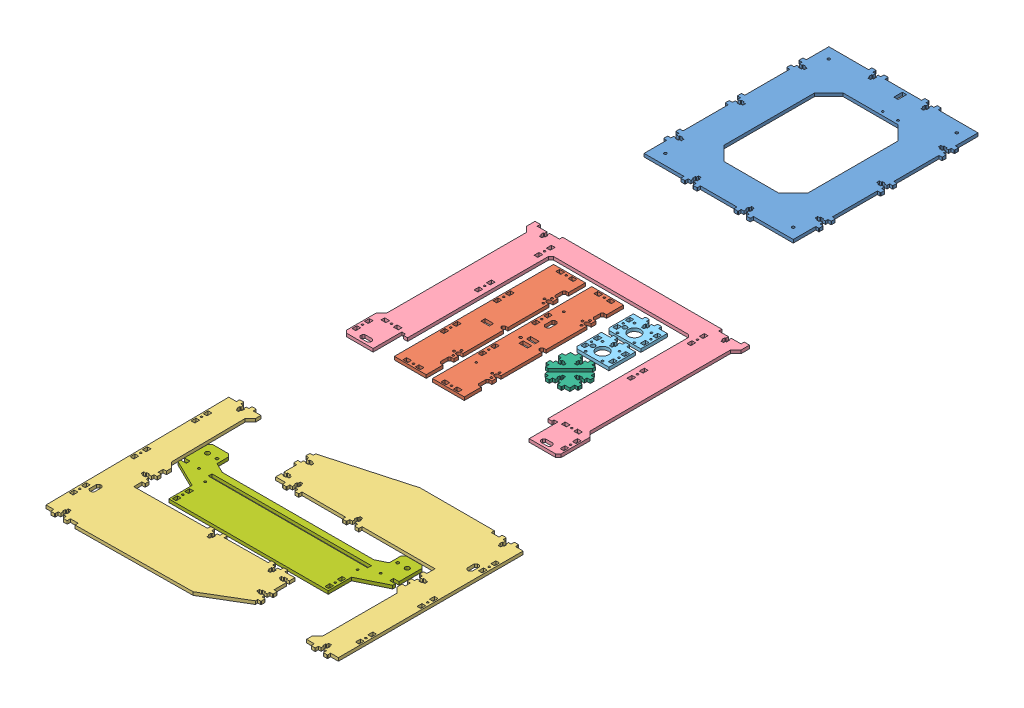
SolidWorks assembly frame_cut, configuration Défaut. Lengths in mm.
Overall size (619.45 6 1513.45).
11 component instances, 7 part files, 18 mates.
Components (placement in the parent):
- frame_bottom-1: frame_bottom [Défaut] at (-159.4463 3 -569.6458) size (293 6 360)
- frame_face-1: frame_face [front] at (-105.9772 3 20.9916) x (0 0 1) z (0 1 0) size (300 60 6)
- frame_face-2: frame_face [rear] at (-178.0549 3 20.72) x (0 0 1) z (0 1 0) size (300 60 6)
- frame_side-1: frame_side [left] at (234.7931 3 540.945) x (0 -1 0) z (0 0 -1) size (6 360 360)
- frame_side-2: frame_side [right] at (-291.5281 3 567.2933) x (0 -1 0) z (0.01087 0 0.999941) size (6 360 360)
- frame_middle-1: frame_middle [Défaut] at (-89.8091 3 -142.0894) x (1 0 0) z (0 1 0) size (404 360 6)
- frame_z_motor-1: frame_z_motor [Défaut] at (-16.2154 3 -98.6938) x (1 0 0) z (0 0 -1) size (64 6 56)
- frame_z_motor_holder-1: frame_z_motor_holder [Défaut] at (-34.2399 3 52.0112) x (0 1 0) z (0 0 1) size (6 53 53)
- frame_top-1: frame_top [Défaut] at (-34.0501 0 571.4756) x (-1 0 0.000948) z (-0.000948 0 -1) size (404 6 130)
- frame_z_motor-4: frame_z_motor [Défaut] at (-16.2267 3 -38.6772) x (1 0 0) z (0 0 -1) size (64 6 56)
- frame_z_motor_holder-4: frame_z_motor_holder [Défaut] at (2.4152 3 3.4437) x (0 1 0) z (0 0 -1) size (6 53 53)
Mates (geometry in assembly coordinates):
- Coïncidente1: coincident anti-aligned: plane of assembly through (0 0 0) normal (0 1 0); plane of frame_middle-1 through (-89.8091 0 -142.0894) normal (0 -1 0)
- Coïncidente2: coincident anti-aligned: plane of assembly through (0 0 0) normal (0 1 0); plane of frame_top-1 through (-34.0501 0 571.4756) normal (0 -1 0)
- Coïncidente3: coincident anti-aligned: plane of assembly through (0 0 0) normal (0 1 0); plane of frame_face-2 through (-148.0549 0 -64.28) normal (0 -1 0)
- Coïncidente4: coincident anti-aligned: plane of assembly through (0 0 0) normal (0 1 0); plane of frame_face-1 through (-75.9772 0 -64.0084) normal (0 -1 0)
- Coïncidente5: coincident anti-aligned: plane of assembly through (0 0 0) normal (0 1 0); plane of frame_side-1 through (234.7931 0 540.945) normal (0 -1 0)
- Coïncidente6: coincident anti-aligned: plane of assembly through (0 0 0) normal (0 1 0); plane of frame_side-2 through (-291.5281 0 567.2933) normal (0 -1 0)
- Coïncidente7: coincident anti-aligned: plane of assembly through (0 0 0) normal (0 1 0); plane of frame_z_motor-1 through (-16.2154 0 -98.6938) normal (0 -1 0)
- Coïncidente8: coincident anti-aligned: plane of assembly through (0 0 0) normal (0 1 0); plane of frame_z_motor_holder-1 through (-34.2399 0 52.0112) normal (0 -1 0)
- Coïncidente9: coincident anti-aligned: plane of assembly through (0 0 0) normal (0 1 0); plane of frame_z_motor-4 through (-16.2267 0 -38.6772) normal (0 -1 0)
- Coïncidente10: coincident anti-aligned: plane of assembly through (0 0 0) normal (0 1 0); plane of frame_z_motor_holder-4 through (2.4152 0 3.4437) normal (0 -1 0)
- Coïncidente11: coincident anti-aligned: plane of frame_bottom-1 through (-159.4463 0 -569.6458) normal (0 -1 0); plane of assembly through (0 0 0) normal (0 1 0)
- Parallèle7: parallel aligned: line of frame_middle-1 through (-281.8091 6 -156.0894) axis (0 0 1); line of frame_face-2 through (-204.0549 6 -129.28) axis (0 0 1)
- Parallèle8: parallel aligned: line of frame_middle-1 through (-281.8091 6 -156.0894) axis (0 0 1); line of frame_face-1 through (-131.9772 6 -129.0084) axis (0 0 1)
- Parallèle9: parallel anti-aligned: line of frame_middle-1 through (-281.8091 6 -156.0894) axis (0 0 1); line of frame_z_motor-4 through (-48.2267 6 -17.6772) axis (0 0 -1)
- Parallèle10: parallel anti-aligned: line of frame_middle-1 through (-281.8091 6 -156.0894) axis (0 0 1); line of frame_z_motor-1 through (-48.2154 6 -77.6938) axis (0 0 -1)
- Parallèle11: parallel aligned: line of frame_middle-1 through (-281.8091 6 -156.0894) axis (0 0 1); line of frame_z_motor_holder-4 through (-44.5848 6 -1.5563) axis (0 0 1)
- Parallèle13: parallel aligned: line of frame_z_motor-1 through (15.7846 6 -123.6938) axis (0 0 1); line of frame_z_motor-4 through (15.7733 6 -63.6772) axis (0 0 1)
- Parallèle14: parallel anti-aligned: line of frame_z_motor_holder-1 through (7.7601 6 10.0112) axis (-0.707107 0 0.707107); line of frame_z_motor_holder-4 through (-39.5848 6 45.4437) axis (0.707107 0 -0.707107)
